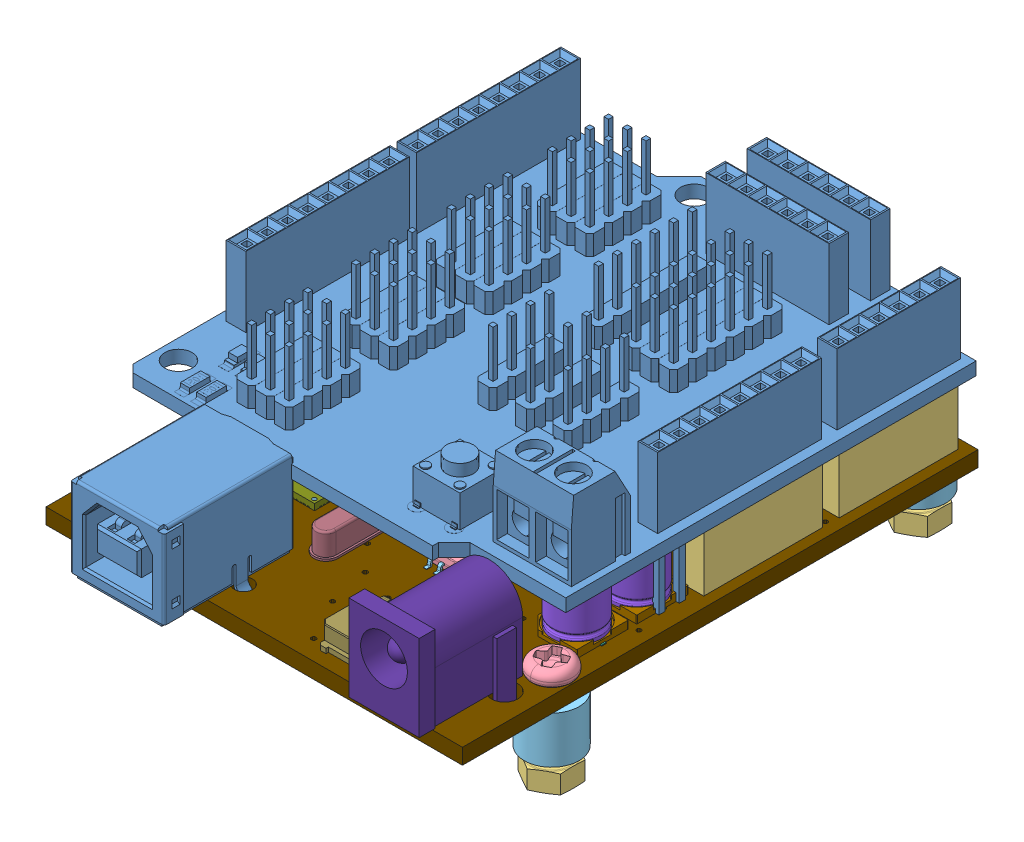
SolidWorks assembly AU, configuration Predeterminado. Lengths in mm.
Overall size (54.69 31.54 75.71).
44 component instances, 23 part files, 19 mates.
Components (placement in the parent):
- Arduino Sensor Board V1-1: Arduino Sensor Board V1 [Predeterminado] at (-2.4496 -2.4606 58.16) size (53.65 20.91 58.16)
- ArduinoUno-1: ArduinoUno [Predeterminado] at (-77.0404 -6.9097 61.6865) x (0 0 -1) z (1 0 0) size (74.75 15.48 53.34)
  - Final-1: Final [Predeterminado] at (-36.0382 -5.851 101.423) size (74.75 15.48 53.34)
    - Stackable Female Pin Header_Default-1: Stackable Female Pin Header_Default [Predeterminado] at (23.9415 1.1201 -50.7298) size (20.32 8.3 2.54)
    - Stackable Female Pin Header_6 Way-1: Stackable Female Pin Header_6 Way [Predeterminado] at (33.5006 2 -2.5872) size (15.24 8.3 2.54)
    - User Library-SOIC-8_Default-1: User Library-SOIC-8_Default [Predeterminado] at (20.4108 1.85 -20.3024) x (0 0 -1) z (1 0 0) size (5 1.75 6.01)
      - User Library-SOIC-8_SOIC-8_Body_1_Default-1: User Library-SOIC-8_SOIC-8_Body_1_Default [Predeterminado] at origin size (5 1.6 4)
      - User Library-SOIC-8_SOIC-8_Pins_1_Default-1: User Library-SOIC-8_SOIC-8_Pins_1_Default [Predeterminado] at origin size (4.23 0.99 6.01)
    - User Library-ALU-D8_Default-1: User Library-ALU-D8_Default [Predeterminado] at (28.1214 1.8 -5.7935) x (0 0 -1) z (0 1 0) size (7 6.6 7.7)
      - User Library-ALU-D8_Pins_1_Default-1: User Library-ALU-D8_Pins_1_Default [Predeterminado] at origin size (7 0.65 0.4)
      - User Library-ALU-D8_Beschriftung_1_Default-1: User Library-ALU-D8_Beschriftung_1_Default [Predeterminado] at origin size (4.35 4.98 0.11)
      - User Library-ALU-D8_K_X_F6rper_1_Default-1: User Library-ALU-D8_K_X_F6rper_1_Default [Predeterminado] at origin size (6.3 6.3 7)
      - User Library-ALU-D8_Fuss_1_Default-1: User Library-ALU-D8_Fuss_1_Default [Predeterminado] at origin size (6.6 6.6 1)
    - User Library-ALU-D8_Default-2: User Library-ALU-D8_Default [Predeterminado] at (20.4464 1.8 -5.7935) x (0 0 -1) z (0 1 0) size (7 6.6 7.7)
      - User Library-ALU-D8_Pins_1_Default-1: User Library-ALU-D8_Pins_1_Default [Predeterminado] at origin size (7 0.65 0.4)
      - User Library-ALU-D8_Beschriftung_1_Default-1: User Library-ALU-D8_Beschriftung_1_Default [Predeterminado] at origin size (4.35 4.98 0.11)
      - User Library-ALU-D8_K_X_F6rper_1_Default-1: User Library-ALU-D8_K_X_F6rper_1_Default [Predeterminado] at origin size (6.3 6.3 7)
      - User Library-ALU-D8_Fuss_1_Default-1: User Library-ALU-D8_Fuss_1_Default [Predeterminado] at origin size (6.6 6.6 1)
    - Stackable Female Pin Header_Default-2: Stackable Female Pin Header_Default [Predeterminado] at (45.7158 1.1368 -50.806) size (20.32 8.3 2.54)
    - LED 1206_Default-1: LED 1206_Default [Predeterminado] at (28.1068 2 -36.9237) x (0 0 -1) z (1 0 0) size (1.6 1.1 3.2)
    - LED 1206_Default-2: LED 1206_Default [Predeterminado] at (58.3346 2 -36.8813) x (0 0 -1) z (1 0 0) size (1.6 1.1 3.2)
    - Header Vertical 2.54mm Pitch2_Header 6 Way-1: Header Vertical 2.54mm Pitch2_Header 6 Way [Predeterminado] at (62.2731 2 -29.1415) size (5.08 8.88 7.62)
    - SO 369A_Standard-1: SO 369A_Standard [Predeterminado] at (5.5398 2 -17.4191) x (0 0 -1) z (0 1 0) size (6.6 10.1 2.4)
    - Stackable Female Pin Header_6 Way-2: Stackable Female Pin Header_6 Way [Predeterminado] at (50.8347 2 -2.5872) size (15.24 8.3 2.54)
    - XTAL Small_Default-1: XTAL Small_Default [Predeterminado] at (14.2222 2 -30.4346) x (1 0 0) z (0 1 0) size (10.67 3.05 5.63)
    - LED 1206_Default-3: LED 1206_Default [Predeterminado] at (28.1068 2 -41.994) x (0 0 -1) z (1 0 0) size (1.6 1.1 3.2)
    - User Library-QFN32 (FTDI)_Default-1: User Library-QFN32 (FTDI)_Default [Predeterminado] at (19.2089 2.05 -38.1588) x (-1 0 0) z (0 1 0) size (5 5 0.81)
      - User Library-QFN32 (FTDI)_Beschriftung_1_Default-1: User Library-QFN32 (FTDI)_Beschriftung_1_Default [Predeterminado] at origin size (0.51 0.51 0.05)
      - User Library-QFN32 (FTDI)_Anschl_X_FCsse_1_Default-1: User Library-QFN32 (FTDI)_Anschl_X_FCsse_1_Default [Predeterminado] x (0 -1 0) z (0 0 1) size (3.86 0.12 0.12)
      - User Library-QFN32 (FTDI)_K_X_F6rper_1_Default-1: User Library-QFN32 (FTDI)_K_X_F6rper_1_Default [Predeterminado] at origin size (5 5 0.8)
    - User Library-dc range - dc connector[4840_2201]_Default-1: User Library-dc range - dc connector[4840_2201]_Default [Predeterminado] at (11.794 2 -12.8354) x (0 0 1) z (-1 0 0) size (9.51 14.5 13.83)
    - PCB_Final_Default-1: PCB_Final_Default [Predeterminado] at origin size (68.58 2 53.34)
    - LED 1206_Default-4: LED 1206_Default [Predeterminado] at (28.142 2 -34.2868) x (0 0 -1) z (1 0 0) size (1.6 1.1 3.2)
    - User Library-67068-0000-molex_Default-1: User Library-67068-0000-molex_Default [Predeterminado] at (-6.1546 2 -38.0545) x (0.002421 0 0.999997) z (-0.999997 0 0.002421) size (15.13 15.48 17)
    - IC DIP 28_Default-1: IC DIP 28_Default [Predeterminado] at (51.4233 4.3498 -16.4837) x (0 0.005002 0.999987) z (-1 0 0) size (7.87 6.22 35.94)
- M3 Nut-1: M3 Nut [Predeterminado] at (21.8426 -23.7606 83.7547) x (1 0 0) z (0 -1 0) size (6.27 6.27 2.71)
- M3x10 Philips Screw-1: M3x10 Philips Screw [Predeterminado] at (21.8426 -10.7606 83.7547) x (-0.88631 0 0.463093) z (0 1 0) size (5.3 5.3 11.8)
- separador-1: separador [Predeterminado] at (16.7626 -18.7606 31.6847) x (1 0 0) z (0 1 0) size (7 7 6)
- separador-2: separador [Predeterminado] at (-11.1774 -12.7606 31.6847) x (1 0 0) z (0 -1 0) size (7 7 6)
- separador-3: separador [Predeterminado] at (21.8426 -12.7606 83.7547) x (1 0 0) z (0 -1 0) size (7 7 6)
- M3x10 Philips Screw-2: M3x10 Philips Screw [Predeterminado] at (16.7626 -10.7606 31.6847) x (1 0 0) z (0 1 0) size (5.3 5.3 11.8)
- M3x10 Philips Screw-3: M3x10 Philips Screw [Predeterminado] at (-11.1774 -10.7606 31.6847) x (1 0 0) z (0 1 0) size (5.3 5.3 11.8)
- M3 Nut-2: M3 Nut [Predeterminado] at (16.7626 -23.7606 31.6847) x (1 0 0) z (0 -1 0) size (6.27 6.27 2.71)
- M3 Nut-3: M3 Nut [Predeterminado] at (-11.1774 -23.7606 31.6847) x (0.99989 0 -0.014845) z (0 -1 0) size (6.27 6.27 2.71)
Mates (geometry in assembly coordinates):
- Coincidente1: coincident: plane of Arduino Sensor Board V1-1 through (22.2954 -2.4606 33.69) normal (1 0 0); plane of ArduinoUno-1/Final-1/Stackable Female Pin Header_6 Way-2 through (22.2954 -6.4606 33.69) normal (-1 0 0)
- Coincidente2: coincident: plane of Arduino Sensor Board V1-1 through (21.4954 -2.4606 33.69) normal (0 0 -1); plane of ArduinoUno-1/Final-1/Stackable Female Pin Header_6 Way-2 through (22.2954 -6.4606 33.69) normal (0 0 1)
- Coincidente3: coincident: plane of Arduino Sensor Board V1-1 through (-2.4452 -2.4606 58.5355) normal (0 -1 0); plane of ArduinoUno-1/Final-1/Stackable Female Pin Header_6 Way-2 through (23.0654 -2.4606 48.16) normal (0 1 0)
- Coincidente4: coincident: plane of ArduinoUno-1/Final-1/PCB_Final_Default-1 through (-2.3058 -12.7606 131.309) normal (0 -1 0); plane of separador-1 through (16.7626 -12.7606 31.6847) normal (0 1 0)
- Concéntrica1: concentric: circle of ArduinoUno-1/Final-1/PCB_Final_Default-1; circle of separador-1
- Coincidente6: coincident: circle of ArduinoUno-1/Final-1/PCB_Final_Default-1; circle of separador-3
- Coincidente7: coincident: circle of ArduinoUno-1/Final-1/PCB_Final_Default-1; circle of separador-2
- Concéntrica2: concentric: circle of M3 Nut-1; circle of separador-3
- Distancia1: distance = 1 mm: plane of M3 Nut-1 through (21.8426 -19.7606 83.7547) normal (0 1 0); plane of separador-3 through (21.8426 -18.7606 83.7547) normal (0 -1 0)
- Concéntrica3: concentric: circle of ArduinoUno-1/Final-1/PCB_Final_Default-1; circle of M3x10 Philips Screw-1
- Coincidente9: coincident: plane of ArduinoUno-1/Final-1/PCB_Final_Default-1 through (-2.3058 -10.7606 131.309) normal (0 1 0); plane of M3x10 Philips Screw-1 through (22.5835 -10.7606 85.1728) normal (0 -1 0)
- Coincidente10: coincident: plane of ArduinoUno-1/Final-1/PCB_Final_Default-1 through (-2.3058 -10.7606 131.309) normal (0 1 0); plane of M3x10 Philips Screw-2 through (16.7626 -10.7606 30.0847) normal (0 -1 0)
- Concéntrica4: concentric: circle of ArduinoUno-1/Final-1/PCB_Final_Default-1; circle of M3x10 Philips Screw-2
- Coincidente11: coincident: plane of ArduinoUno-1/Final-1/PCB_Final_Default-1 through (-2.3058 -10.7606 131.309) normal (0 1 0); plane of M3x10 Philips Screw-3 through (-11.1774 -10.7606 30.0847) normal (0 -1 0)
- Concéntrica5: concentric: circle of ArduinoUno-1/Final-1/PCB_Final_Default-1; circle of M3x10 Philips Screw-3
- Distancia2: distance = 1 mm: plane of M3 Nut-2 through (16.7626 -19.7606 31.6847) normal (0 1 0); plane of separador-1 through (16.7626 -18.7606 31.6847) normal (0 -1 0)
- Concéntrica6: concentric: circle of separador-1; circle of M3 Nut-2
- Concéntrica7: concentric: circle of separador-2; circle of M3 Nut-3
- Distancia3: distance = 1 mm: plane of M3 Nut-3 through (-11.1774 -19.7606 31.6847) normal (0 1 0); plane of separador-2 through (-11.1774 -18.7606 31.6847) normal (0 -1 0)
